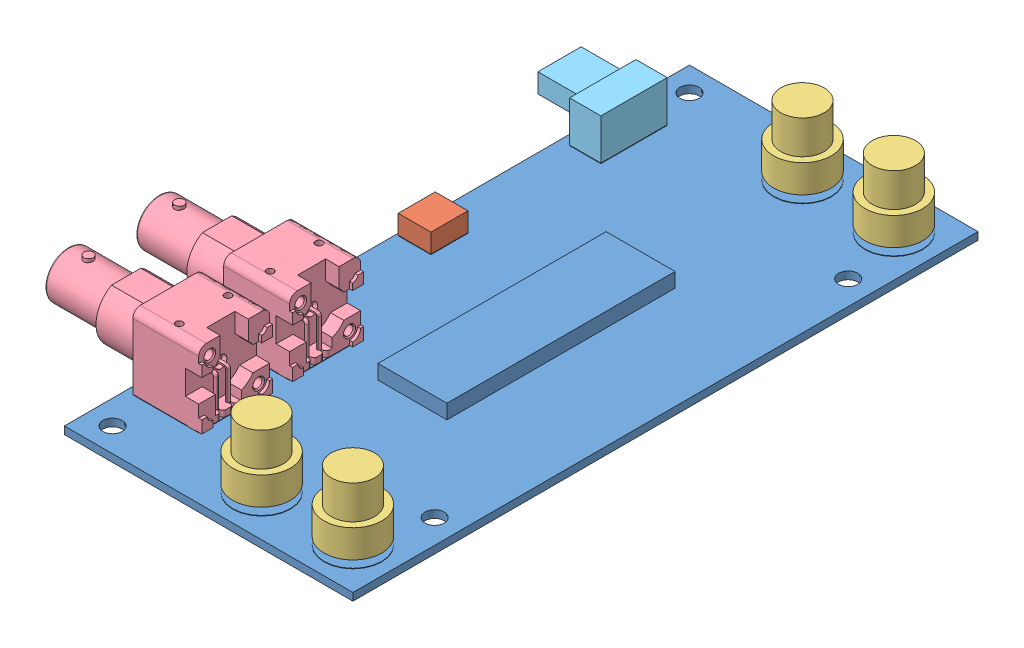
SolidWorks assembly Assembly Attempt 1, configuration Default. Lengths in mm.
Overall size (79.33 19.99 130).
9 component instances, 5 part files, 20 mates.
Components (placement in the parent):
- PCB-1: PCB [Default] at (-23.8374 -7.4636 63.7615) size (60 4.57 130)
- USB_Connector-1: USB_Connector [Default] at (-16.5785 -5.7936 -12.9019) x (-1 0 0) z (0 0 -1) size (6.8 3.95 7.7)
- Button-1: Button [Default] at (27.6626 1.5064 -57.2385) x (0.509471 0 -0.860488) z (0.860488 0 0.509471) size (12 14.3 12)
- Button-2: Button [Default] at (27.6626 1.5064 55.2615) x (-0.304345 0 -0.952562) z (0.952562 0 -0.304345) size (12 14.3 12)
- Button-3: Button [Default] at (8.6626 1.5064 -57.2385) x (-0.088883 0 -0.996042) z (0.996042 0 -0.088883) size (12 14.3 12)
- BNC-1: BNC [Default] at (-43.1654 1.8264 43.6628) x (0 0 1) z (-1 0 0) size (14.76 19.99 35.18)
- Button-4: Button [Default] at (8.6626 1.5064 55.2615) x (0.505042 0 0.863095) z (-0.863095 0 0.505042) size (12 14.3 12)
- BNC-2: BNC [Default] at (-43.1654 1.8264 24.7628) x (0 0 1) z (-1 0 0) size (14.76 19.99 35.18)
- Switch-1: Switch [Default] at (-15.2925 -5.7936 -53.0647) x (0 0 1) z (0 -1 0) size (13.8 15.5 8.5)
Mates (geometry in assembly coordinates):
- Concentric1: concentric anti-aligned: circle of PCB-1; circle of Button-4
- Concentric2: concentric anti-aligned: circle of PCB-1; circle of Button-2
- Coincident2: coincident anti-aligned: plane of PCB-1 through (8.6626 -5.7936 55.2615) normal (0 1 0); plane of Button-4 through (8.6626 -5.7936 55.2615) normal (0 -1 0)
- Coincident3: coincident anti-aligned: plane of PCB-1 through (27.6626 -5.7936 55.2615) normal (0 1 0); plane of Button-2 through (27.6626 -5.7936 55.2615) normal (0 -1 0)
- Concentric3: concentric anti-aligned: circle of PCB-1; circle of Button-3
- Concentric4: concentric anti-aligned: circle of PCB-1; circle of Button-1
- Coincident4: coincident anti-aligned: plane of PCB-1 through (27.6626 -5.7936 -57.2385) normal (0 1 0); plane of Button-1 through (27.6626 -5.7936 -57.2385) normal (0 -1 0)
- Coincident5: coincident anti-aligned: plane of PCB-1 through (8.6626 -5.7936 -57.2385) normal (0 1 0); plane of Button-3 through (8.6626 -5.7936 -57.2385) normal (0 -1 0)
- Coincident6: coincident anti-aligned: plane of PCB-1 through (-22.3374 -5.7936 36.4815) normal (0 1 0); plane of BNC-1 through (-22.3374 -5.7936 36.2841) normal (0 -1 0)
- Coincident9: coincident anti-aligned: plane of PCB-1 through (-22.3374 -5.7936 32.1415) normal (0 1 0); plane of BNC-2 through (-22.3374 -5.7936 17.3841) normal (0 -1 0)
- Coincident10: coincident aligned: line of PCB-1 through (-22.3374 -5.7936 51.0415) axis (1 0 0); line of BNC-1 through (-17.6384 -5.7936 51.0415) axis (1 0 0)
- Coincident11: coincident aligned: line of PCB-1 through (-22.3374 -5.7936 36.4815) axis (0 0 1); line of BNC-1 through (-22.3374 -5.7936 36.2841) axis (0 0 1)
- Coincident12: coincident aligned: line of PCB-1 through (-22.3374 -5.7936 32.1415) axis (1 0 0); line of BNC-2 through (-17.6384 -5.7936 32.1415) axis (1 0 0)
- Coincident13: coincident aligned: line of PCB-1 through (-22.3374 -5.7936 17.3815) axis (0 0 1); line of BNC-2 through (-22.3374 -5.7936 17.3841) axis (0 0 1)
- Coincident14: coincident anti-aligned: plane of PCB-1 through (-23.2785 -5.7936 -12.9019) normal (0 1 0); plane of USB_Connector-1 through (-16.5785 -5.7936 -5.2019) normal (0 -1 0)
- Coincident15: coincident anti-aligned: plane of PCB-1 through (-21.6925 -5.7936 -53.0647) normal (0 1 0); plane of Switch-1 through (-21.7925 -5.7936 -53.0647) normal (0 -1 0)
- Coincident16: coincident aligned: line of PCB-1 through (-21.6925 -5.7936 -39.2647) axis (1 0 0); line of Switch-1 through (-21.7925 -5.7936 -39.2647) axis (1 0 0)
- Coincident17: coincident anti-aligned: line of PCB-1 through (-15.2925 -5.7936 -39.2647) axis (0 0 -1); line of Switch-1 through (-15.2925 -5.7936 -53.0647) axis (0 0 1)
- Coincident21: coincident aligned: line of PCB-1 through (-23.2785 -5.7936 -5.2019) axis (1 0 0); line of USB_Connector-1 through (-23.3785 -5.7936 -5.2019) axis (1 0 0)
- Coincident22: coincident aligned: line of PCB-1 through (-16.5785 -5.7936 -5.2019) axis (0 0 -1); line of USB_Connector-1 through (-16.5785 -5.7936 -5.2019) axis (0 0 -1)
